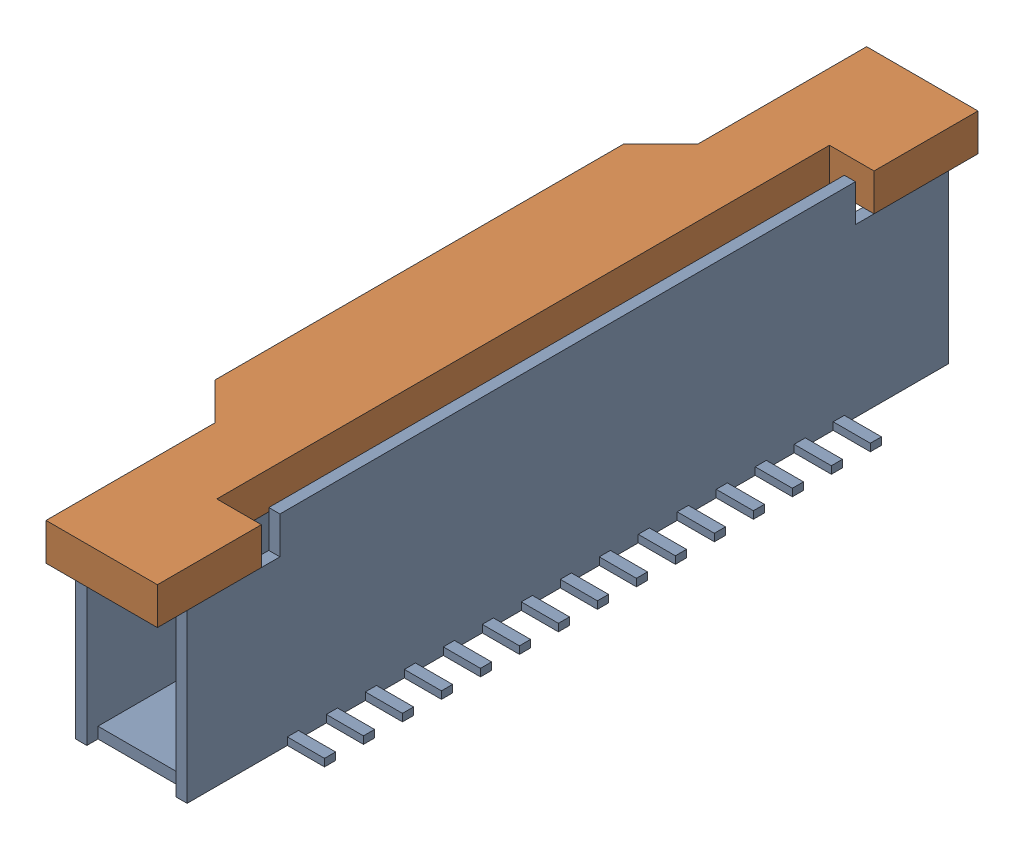
SolidWorks assembly CameraAssembly, configuration Défaut. Lengths in mm.
Overall size (5 5.5 22.1).
2 component instances, 2 part files, 0 mates.
Components (placement in the parent):
- Camera-1: Camera [Défaut] at (7.3885 2.9159 0) size (5 5.5 20.5)
- CameraTop-1: CameraTop [Défaut] at (6.8885 8.4159 0) x (1 0 0) z (0 0 -1) size (4 1 22.1)
